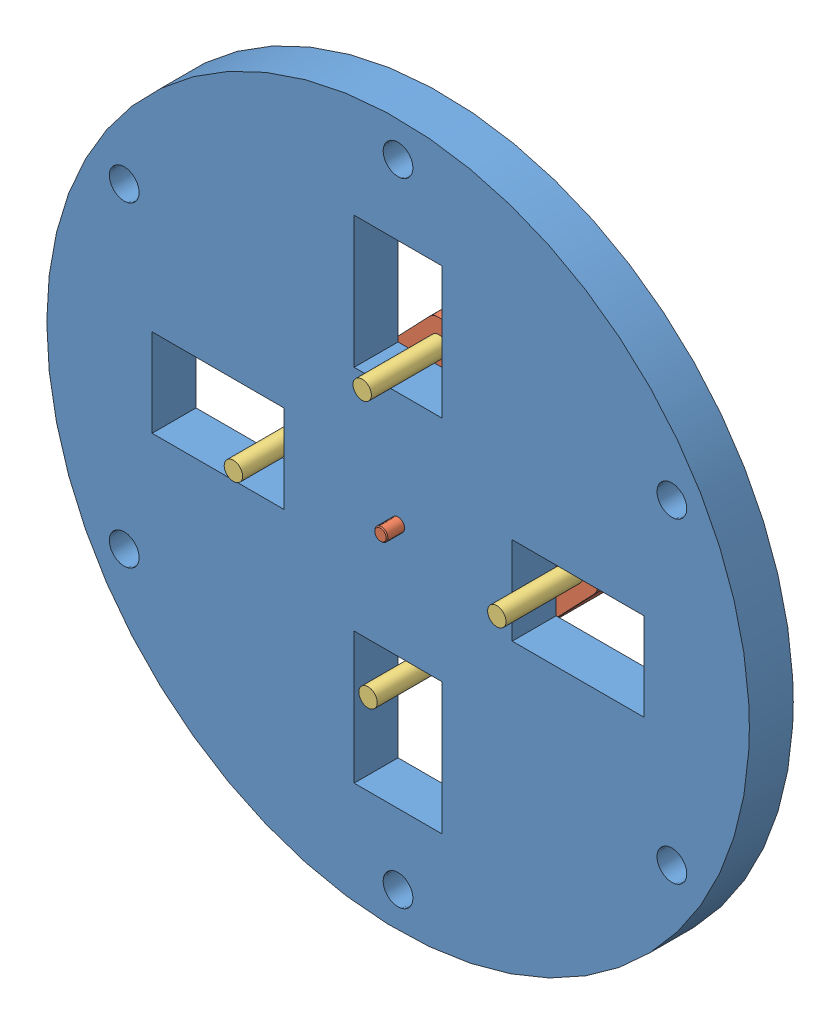
SolidWorks assembly rwv4, configuration Default. Lengths in mm.
Overall size (80 80 19.15).
6 component instances, 3 part files, 8 mates.
Components (placement in the parent):
- collar-1: collar [Default] at (-24.4446 13.8108 3.5162) size (80 80 5)
- 2610T-1: 2610T [Default] at (-24.4446 13.8108 -5.8838) x (0.691224 0.72264 0) z (0 0 1) size (37.25 26 17.4)
- screw-1: screw [Default] at (-24.1113 -1.1855 2.2662) size (2.1 2.1 10)
- screw-2: screw [Default] at (-39.4409 13.4776 2.2662) size (2.1 2.1 10)
- screw-3: screw [Default] at (-24.7778 28.8071 2.2662) x (0.822597 0.568624 0) z (0 0 1) size (2.1 2.1 10)
- screw-4: screw [Default] at (-9.4483 14.144 2.2662) size (2.1 2.1 10)
Mates (geometry in assembly coordinates):
- Concentric1: concentric anti-aligned: circle of collar-1; circle of 2610T-1
- Coincident2: coincident anti-aligned: plane of collar-1 through (-24.4446 13.8108 3.5162) normal (0 0 -1); plane of 2610T-1 through (-26.6125 15.8845 3.5162) normal (0 0 1)
- Concentric2: concentric aligned: circle of 2610T-1; circle of screw-1
- Coincident3: coincident aligned: plane of 2610T-1 through (-24.0833 -2.4486 2.2662) normal (0 0 -1); plane of screw-1 through (-24.1113 -1.1855 2.2662) normal (0 0 -1)
- Concentric3: concentric aligned: circle of 2610T-1; circle of screw-2
- Coincident5: coincident aligned: plane of 2610T-1 through (-24.0833 -2.4486 2.2662) normal (0 0 -1); plane of screw-2 through (-39.4409 13.4776 2.2662) normal (0 0 -1)
- Coincident6: coincident aligned: circle of 2610T-1; circle of screw-4
- Coincident7: coincident aligned: circle of 2610T-1; circle of screw-3
